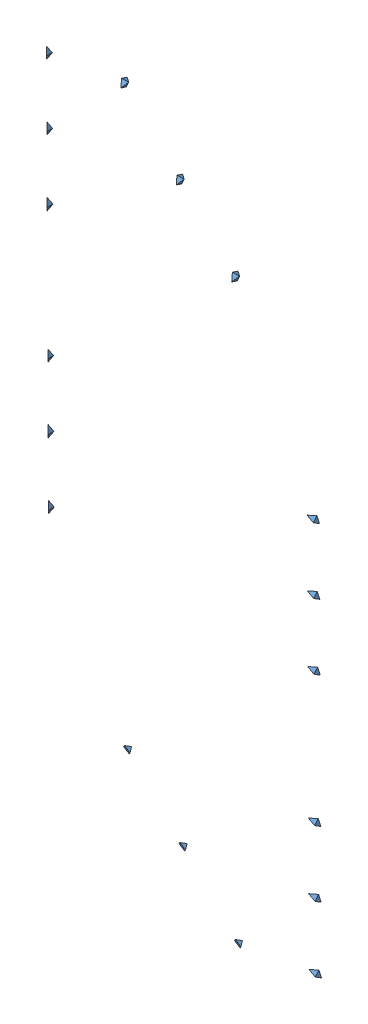
SolidWorks assembly Złożenie3^Złożenie2, configuration Domyślna. Lengths in mm.
Overall size (2214.79 1428.26 2205.7).
18 component instances, 1 part files, 0 mates.
Components (placement in the parent):
- Diamond-1: Diamond [Domyślna] at origin size (20 39.8 19.8)
- Diamond-2: Diamond [Domyślna] at (-225.0712 0 -223.9402) size (20 39.8 19.8)
- Diamond-3: Diamond [Domyślna] at (-450.1424 0 -447.8804) size (20 39.8 19.8)
- Diamond-4: Diamond [Domyślna] at (-900.2848 0 -895.7607) size (20 39.8 19.8)
- Diamond-5: Diamond [Domyślna] at (-1125.356 0 -1119.7009) size (20 39.8 19.8)
- Diamond-6: Diamond [Domyślna] at (-1350.4272 0 -1343.6411) size (20 39.8 19.8)
- Diamond-7: Diamond [Domyślna] at (453.667 -1379.3558 -455.9582) x (0.822294 0.540309 0.178604) z (0.178604 -0.543038 0.820494) size (20 39.8 19.8)
- Diamond-8: Diamond [Domyślna] at (228.5958 -1379.3558 -679.8984) x (0.822294 0.540309 0.178604) z (0.178604 -0.543038 0.820494) size (20 39.8 19.8)
- Diamond-9: Diamond [Domyślna] at (3.5246 -1379.3558 -903.8386) x (0.822294 0.540309 0.178604) z (0.178604 -0.543038 0.820494) size (20 39.8 19.8)
- Diamond-10: Diamond [Domyślna] at (-446.6178 -1379.3558 -1351.719) x (0.822294 0.540309 0.178604) z (0.178604 -0.543038 0.820494) size (20 39.8 19.8)
- Diamond-11: Diamond [Domyślna] at (-671.689 -1379.3558 -1575.6591) x (0.822294 0.540309 0.178604) z (0.178604 -0.543038 0.820494) size (20 39.8 19.8)
- Diamond-12: Diamond [Domyślna] at (-896.7602 -1379.3558 -1799.5993) x (0.822294 0.540309 0.178604) z (0.178604 -0.543038 0.820494) size (20 39.8 19.8)
- Diamond-13: Diamond [Domyślna] at (642.9147 -983.7909 -7.4574) x (-0.013985 0.912623 -0.408563) z (-0.408563 0.367721 0.835379) size (20 39.8 19.8)
- Diamond-14: Diamond [Domyślna] at (548.2735 -696.0382 87.6618) x (-0.013985 0.912623 -0.408563) z (-0.408563 0.367721 0.835379) size (20 39.8 19.8)
- Diamond-15: Diamond [Domyślna] at (453.6323 -408.2855 182.781) x (-0.013985 0.912623 -0.408563) z (-0.408563 0.367721 0.835379) size (20 39.8 19.8)
- Diamond-16: Diamond [Domyślna] at (-1336.2591 -983.7909 -1976.6856) x (0.408628 0.912623 0.011927) z (-0.83331 0.367721 0.412766) size (20 39.8 19.8)
- Diamond-17: Diamond [Domyślna] at (-1430.9003 -696.0382 -1881.5664) x (0.408628 0.912623 0.011927) z (-0.83331 0.367721 0.412766) size (20 39.8 19.8)
- Diamond-18: Diamond [Domyślna] at (-1525.5415 -408.2855 -1786.4472) x (0.408628 0.912623 0.011927) z (-0.83331 0.367721 0.412766) size (20 39.8 19.8)
